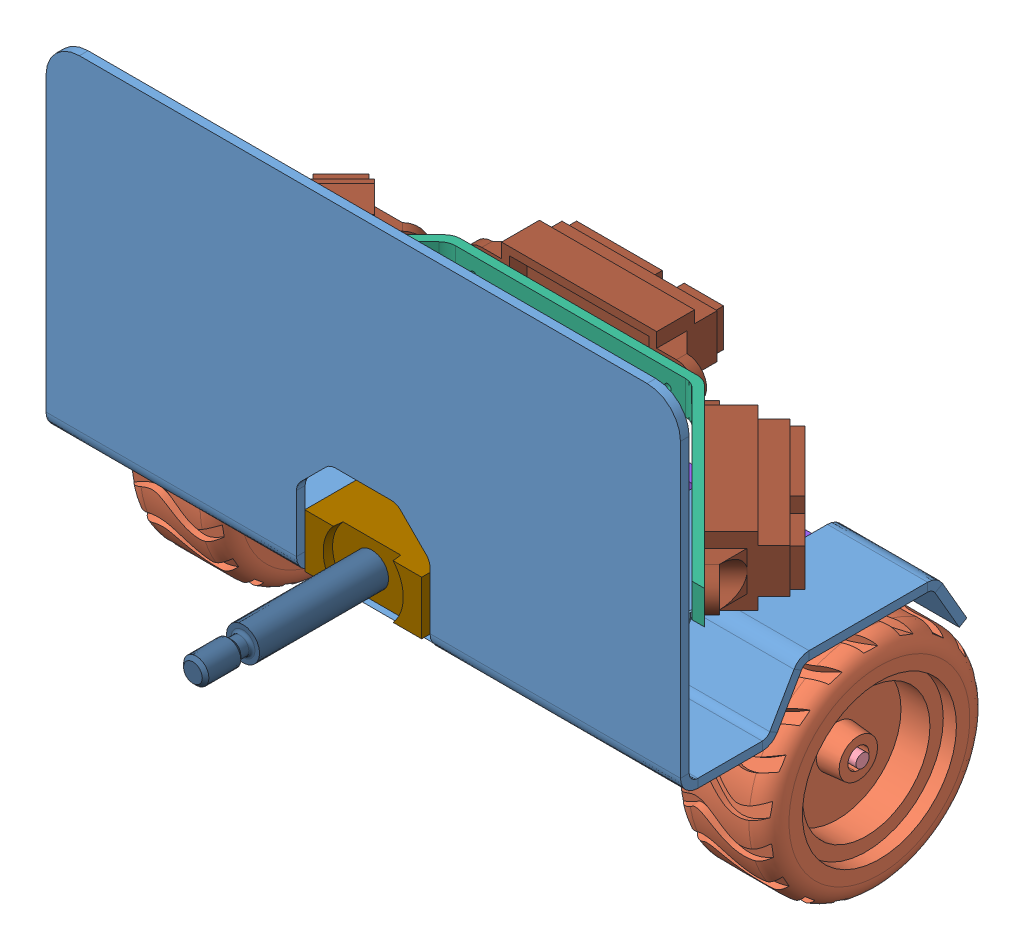
SolidWorks assembly Scout Front End, configuration Default. Lengths in mm.
Overall size (134.15 99.37 90.08).
21 component instances, 11 part files, 35 mates.
Components (placement in the parent):
- Front Baseplate-1: Front Baseplate [Default] at (-76.4634 46.5072 -32.0242) size (120.65 65.15 54.45)
- Pololu Wheel Assembly-1: Pololu Wheel Assembly [Default-_flexible3] at (-26.7168 45.4091 2.1802) x (0 0 1) z (1 0 0) size (42.46 78.6 70.03) (flexible)
  - Pololu 49x19 Wheel-1: Pololu 49x19 Wheel [Default] at (-19.8703 11.8393 2.4418) size (42.46 42.56 19)
  - Pololu Extended Micro Metal Bracket-1: Pololu Extended Micro Metal Bracket [Default] at (-19.8703 6.8393 -18.4366) size (26.6 22.49 26.04)
  - Pololu 298-1 Motor-1: Pololu 298-1 Motor [Default] at (-19.8703 11.8393 -25.1366) x (0 0 -1) z (0 1 0) size (35.87 12 10)
- Pololu Wheel Assembly-2: Pololu Wheel Assembly [Default-_flexible4] at (-126.21 45.4091 -37.5605) x (0 0 -1) z (-1 0 0) size (42.46 78.6 70.03) (flexible)
  - Pololu 49x19 Wheel-1: Pololu 49x19 Wheel [Default] at (-19.8703 11.8393 2.4418) size (42.46 42.56 19)
  - Pololu Extended Micro Metal Bracket-1: Pololu Extended Micro Metal Bracket [Default] at (-19.8703 6.8393 -18.4366) size (26.6 22.49 26.04)
  - Pololu 298-1 Motor-1: Pololu 298-1 Motor [Default] at (-19.8703 11.8393 -25.1366) x (0 0 -1) z (0 1 0) size (35.87 12 10)
- Socket Head Cap Screw_AI-1: Socket Head Cap Screw_AI [HX-SHCS 0.086-56x0.4375x0.4375-N] at (-112.0234 50.3426 -8.6902) x (0 -1 0) z (0.989468 0 0.144748) size (13.3 3.56 3.56)
- Socket Head Cap Screw_AI-2: Socket Head Cap Screw_AI [HX-SHCS 0.086-56x0.4375x0.4375-N] at (-40.9034 50.3426 -26.6902) x (0 -1 0) z (0.390166 0 -0.920744) size (13.3 3.56 3.56)
- Socket Head Cap Screw_AI-3: Socket Head Cap Screw_AI [HX-SHCS 0.086-56x0.4375x0.4375-N] at (-40.9034 50.3426 -8.6902) x (0 -1 0) z (0.700957 0 0.713204) size (13.3 3.56 3.56)
- Socket Head Cap Screw_AI-4: Socket Head Cap Screw_AI [HX-SHCS 0.086-56x0.4375x0.4375-N] at (-112.0234 50.3426 -26.6902) x (0 -1 0) z (-0.920661 0 -0.390363) size (13.3 3.56 3.56)
- Sensor Bar-1: Sensor Bar [Default] at (-76.4634 73.5582 -21.4496) size (116.51 6.35 34.42)
- GP2Y0D810 Sensor-2: GP2Y0D810 Sensor [Default] at (-76.7491 52.0249 -21.9932) x (1 0 0) z (0 -0.642788 0.766044) size (28.32 10.54 8.89)
- Bumper-1: Bumper [Default] at (-76.4634 36.9822 -30.9902) x (-1 0 0) z (0 0 -1) size (69.85 9.53 6.35)
- Mounting Block-1: Mounting Block [Default] at (-76.4634 53.2382 9.2508) size (22.23 10.17 19.05)
- Socket Head Shoulder Screw2_AI-1: Socket Head Shoulder Screw2_AI [SHSSCREW 0.25x1.5-N] at (-76.4634 53.2382 -1.2394) x (0 0 1) z (-1 0 0) size (52.4 9.53 9.53)
- gp2d12-1: gp2d12 [Default] at (-34.6666 73.5582 -4.3153) x (-0.707107 0 -0.707107) z (0.707107 0 -0.707107) size (44.5 18.9 13.5)
- gp2d12-2: gp2d12 [Default] at (-76.4634 73.5582 -22.2751) x (-1 0 0) z (0 0 -1) size (44.5 18.9 13.5)
- gp2d12-3: gp2d12 [Default] at (-118.2602 73.5582 -4.3153) x (-0.707107 0 0.707107) z (-0.707107 0 -0.707107) size (44.5 18.9 13.5)
Mates (geometry in assembly coordinates):
- Coincident1: coincident aligned: plane of Pololu Wheel Assembly-1/Pololu Extended Micro Metal Bracket-1 through (-27.8534 38.5697 -30.9902) normal (0 1 0); plane of Pololu Wheel Assembly-2/Pololu Extended Micro Metal Bracket-1 through (-125.0734 38.5697 -4.3902) normal (0 1 0)
- Coincident2: coincident aligned: plane of Pololu Wheel Assembly-1/Pololu Extended Micro Metal Bracket-1 through (-27.8534 32.5697 -25.1902) normal (0 0 -1); plane of Pololu Wheel Assembly-2/Pololu Extended Micro Metal Bracket-1 through (-125.0734 32.5697 -25.1902) normal (0 0 -1)
- Parallel1: parallel anti-aligned: plane of Pololu Wheel Assembly-2/Pololu Extended Micro Metal Bracket-1 through (-125.0734 32.5697 -10.1902) normal (0 0 1); plane of Front Baseplate-1 through (-36.4584 48.1582 -32.0242) normal (0 0 -1)
- Coincident7: coincident anti-aligned: plane of Front Baseplate-1 through (-116.4684 46.5072 2.2658) normal (0 -1 0); plane of Pololu Wheel Assembly-1/Pololu Extended Micro Metal Bracket-1 through (-51.859 46.5072 -30.9902) normal (0 1 0)
- Coincident8: coincident aligned: plane of Socket Head Cap Screw_AI-3 through (-40.9034 50.3426 -8.6902) normal (0 1 0); plane of Socket Head Cap Screw_AI-4 through (-112.0234 50.3426 -26.6902) normal (0 1 0)
- Coincident9: coincident aligned: plane of Socket Head Cap Screw_AI-1 through (-112.0234 50.3426 -8.6902) normal (0 1 0); plane of Socket Head Cap Screw_AI-2 through (-40.9034 50.3426 -26.6902) normal (0 1 0)
- Coincident10: coincident aligned: plane of Socket Head Cap Screw_AI-1 through (-112.0234 50.3426 -8.6902) normal (0 1 0); plane of Socket Head Cap Screw_AI-4 through (-112.0234 50.3426 -26.6902) normal (0 1 0)
- Concentric3: concentric aligned: cylinder of Socket Head Cap Screw_AI-2; cylinder of Front Baseplate-1
- Concentric4: concentric aligned: cylinder of Front Baseplate-1; cylinder of Socket Head Cap Screw_AI-3
- Concentric5: concentric aligned: cylinder of Front Baseplate-1; cylinder of Socket Head Cap Screw_AI-4
- Concentric6: concentric aligned: cylinder of Front Baseplate-1; cylinder of Socket Head Cap Screw_AI-1
- Coincident11: coincident anti-aligned: plane of Front Baseplate-1 through (-116.4684 48.1582 2.2658) normal (0 1 0); plane of Socket Head Cap Screw_AI-4 through (-112.7174 48.1582 -25.0532) normal (0 -1 0)
- Concentric15: concentric aligned: cylinder of Pololu Wheel Assembly-2/Pololu Extended Micro Metal Bracket-1; cylinder of Socket Head Cap Screw_AI-4
- Concentric16: concentric aligned: cylinder of Pololu Wheel Assembly-1/Pololu Extended Micro Metal Bracket-1; cylinder of Socket Head Cap Screw_AI-2
- Distance1: distance = 25.4 mm aligned: plane of Sensor Bar-1 through (-76.4634 73.5582 -21.4496) normal (0 1 0); plane of Front Baseplate-1 through (-116.4684 48.1582 2.2658) normal (0 1 0)
- Coincident88: coincident aligned: plane of Front Baseplate-1 through (-76.4634 46.5072 -32.0242) normal (1 0 0); plane of Sensor Bar-1 through (-76.4634 73.5582 -21.4496) normal (1 0 0)
- Coincident89: coincident anti-aligned: plane of Front Baseplate-1 through (-64.9064 48.1582 -17.3851) normal (0 0.766044 0.642788); plane of GP2Y0D810 Sensor-2 through (-64.8619 54.8821 -25.3983) normal (0 -0.766044 -0.642788)
- Concentric37: concentric aligned: cylinder of Front Baseplate-1; cylinder of GP2Y0D810 Sensor-2
- Coincident90: coincident anti-aligned: plane of Bumper-1 through (-111.3884 46.5072 -30.9902) normal (0 0 1); plane of Pololu Wheel Assembly-1/Pololu Extended Micro Metal Bracket-1 through (-36.6534 46.5072 -30.9902) normal (0 0 -1)
- Coincident91: coincident aligned: plane of Bumper-1 through (-41.5384 46.5072 -37.3402) normal (0 1 0); line of Front Baseplate-1
- Coincident92: coincident anti-aligned: plane of Front Baseplate-1 through (-76.4634 46.5072 -32.0242) normal (1 0 0); plane of Bumper-1 through (-76.4634 36.9822 -30.9902) normal (-1 0 0)
- Concentric38: concentric aligned: cylinder of Front Baseplate-1; cylinder of Mounting Block-1
- Concentric39: concentric aligned: cylinder of Front Baseplate-1; cylinder of Mounting Block-1
- Coincident93: coincident anti-aligned: plane of Front Baseplate-1 through (-116.4684 48.1582 2.2658) normal (0 1 0); plane of Mounting Block-1 through (-87.5759 48.1582 18.7758) normal (0 -1 0)
- Coincident94: coincident anti-aligned: plane of Mounting Block-1 through (-70.1134 48.1582 3.5358) normal (0 0 -1); plane of Socket Head Shoulder Screw2_AI-1 through (-76.4634 58.0007 3.5358) normal (0 0 1)
- Concentric40: concentric aligned: cylinder of Mounting Block-1; cylinder of Socket Head Shoulder Screw2_AI-1
- Concentric41: concentric aligned: cylinder of gp2d12-1; cylinder of Sensor Bar-1
- Concentric42: concentric aligned: cylinder of Sensor Bar-1; cylinder of gp2d12-1
- Coincident95: coincident anti-aligned: plane of Sensor Bar-1 through (-52.6264 70.3832 -22.2751) normal (0.707107 0 -0.707107); plane of gp2d12-1 through (-50.5885 67.0582 -20.2372) normal (-0.707107 0 0.707107)
- Concentric43: concentric aligned: cylinder of gp2d12-2; cylinder of Sensor Bar-1
- Concentric44: concentric aligned: cylinder of Sensor Bar-1; cylinder of gp2d12-2
- Coincident96: coincident anti-aligned: plane of Sensor Bar-1 through (-46.4073 70.3832 -22.2751) normal (0 0 -1); plane of gp2d12-2 through (-98.9804 67.0582 -22.2751) normal (0 0 1)
- Concentric45: concentric aligned: cylinder of Sensor Bar-1; cylinder of gp2d12-3
- Concentric46: concentric aligned: cylinder of Sensor Bar-1; cylinder of gp2d12-3
- Coincident97: coincident anti-aligned: unknown of Sensor Bar-1; unknown of gp2d12-3
